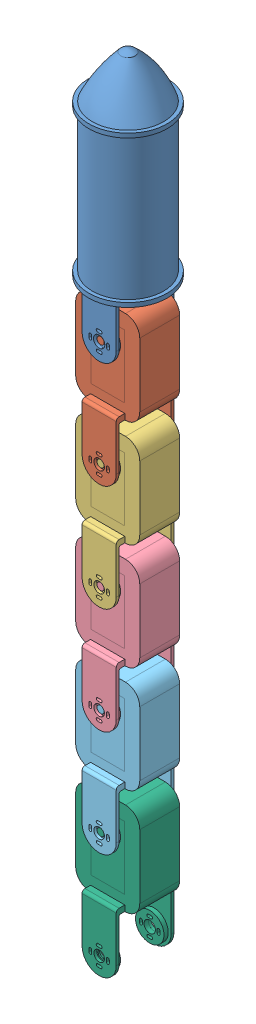
SolidWorks assembly test5_2, configuration 預設. Lengths in mm.
Overall size (55 553.48 55).
6 component instances, 6 part files, 22 mates.
Components (placement in the parent):
- base_link2-2: base_link2 [預設] at origin size (55 179.98 55)
- link1-1: link1 [預設] at (0 -157.7 0) x (0 1 0) z (0 0 -1) size (107 45 40.5)
- link2-1: link2 [預設] at (0 -232.4 0) x (0 1 0) z (0 0 -1) size (107 45 40.5)
- link3-2: link3 [預設] at (0 -307.1 0) x (0 1 0) z (0 0 -1) size (107 45 40.5)
- link4-1: link4 [預設] at (0 -381.8 0) x (0 1 0) z (0 0 -1) size (107 45 40.5)
- link5-1: link5 [預設] at (0 -456.5 0) x (0 1 0) z (0 0 -1) size (107 45 40.5)
Mates (geometry in assembly coordinates):
- 平行相距4: distance = 18.5 mm: plane of base_link2-2 through (0 -83 -18.5) normal (0 0 1); plane of assembly through (0 0 0) normal (0 0 1)
- 平行相距5: distance = 12 mm: plane of assembly through (0 0 0) normal (1 0 0); plane of base_link2-2 through (12 -53 18) normal (1 0 0)
- 平行相距6: distance = 50 mm: plane of assembly through (0 0 0) normal (0 1 0); plane of base_link2-2 through (0 -50 -0.25) normal (0 1 0)
- 同軸心2: concentric: cylinder of base_link2-2 through (0 -83 18) axis (0 0 1) radius 4; cylinder of link1-1 through (0 -83 14) axis (0 0 1) radius 2.5
- 同軸心3: concentric: cylinder of base_link2-2 through (0 -83 -20.5) axis (0 0 1) radius 4; cylinder of link1-1 through (0 -83 -19) axis (0 0 1) radius 2.5
- 平行1: parallel: plane of base_link2-2 through (12 -53 -20.5) normal (1 0 0); plane of link1-1 through (22.5 -127.7 -14) normal (1 0 0)
- 重合/共線/共點8: coincident: plane of base_link2-2 through (0 -83 -18.5) normal (0 0 1); plane of link1-1 through (0 -157.7 -18.5) normal (0 0 1)
- 同軸心4: concentric: cylinder of link1-1 through (0 -157.7 20) axis (0 0 -1) radius 3.7; cylinder of ? through (122.3295 -185.6512 7.75) axis (0 0 -1) radius 2.5
- 重合/共線/共點9: coincident: plane of link1-1 through (22.5 -127.7 -14) normal (1 0 0); plane of ?
- 重合/共線/共點10: coincident: plane of link1-1 through (0 -67.7653 20) normal (0 0 1); plane of ?
- 重合/共線/共點11: coincident: plane of link1-1 through (22.5 -127.7 -14) normal (1 0 0); plane of link2-1 through (22.5 -202.4 -14) normal (1 0 0)
- 同軸心5: concentric: cylinder of link1-1 through (0 -157.7 20) axis (0 0 -1) radius 3.7; cylinder of link2-1 through (0 -157.7 14) axis (0 0 1) radius 2.5
- 重合/共線/共點12: coincident: plane of link1-1 through (0 -67.7653 14) normal (0 0 1); plane of link2-1 through (0 -142.4653 14) normal (0 0 1)
- 重合/共線/共點14: coincident: plane of link2-1 through (22.5 -202.4 -14) normal (1 0 0); plane of link3-2 through (22.5 -277.1 -14) normal (1 0 0)
- 同軸心6: concentric: cylinder of link2-1 through (0 -232.4 -18.5) axis (0 0 -1) radius 4; cylinder of link3-2 through (0 -232.4 -19) axis (0 0 1) radius 2.5
- 重合/共線/共點15: coincident: plane of link2-1 through (0 -142.4653 -14) normal (0 0 -1); plane of link3-2 through (0 -217.1653 -14) normal (0 0 -1)
- 同軸心7: concentric: cylinder of link3-2 through (0 -307.1 20) axis (0 0 -1) radius 3.7; cylinder of link4-1 through (0 -307.1 14) axis (0 0 1) radius 2.5
- 重合/共線/共點16: coincident: plane of link3-2 through (22.5 -277.1 -14) normal (1 0 0); plane of link4-1 through (22.5 -351.8 -14) normal (1 0 0)
- 重合/共線/共點17: coincident: plane of link3-2 through (0 -217.1653 14) normal (0 0 1); plane of link4-1 through (0 -291.8653 14) normal (0 0 1)
- 重合/共線/共點18: coincident: plane of link4-1 through (22.5 -351.8 -14) normal (1 0 0); plane of link5-1 through (22.5 -426.5 -14) normal (1 0 0)
- 同軸心8: concentric: cylinder of link4-1 through (0 -381.8 20) axis (0 0 -1) radius 3.7; cylinder of link5-1 through (0 -381.8 14) axis (0 0 1) radius 2.5
- 重合/共線/共點19: coincident: plane of link4-1 through (0 -291.8653 14) normal (0 0 1); plane of link5-1 through (0 -366.5653 14) normal (0 0 1)
